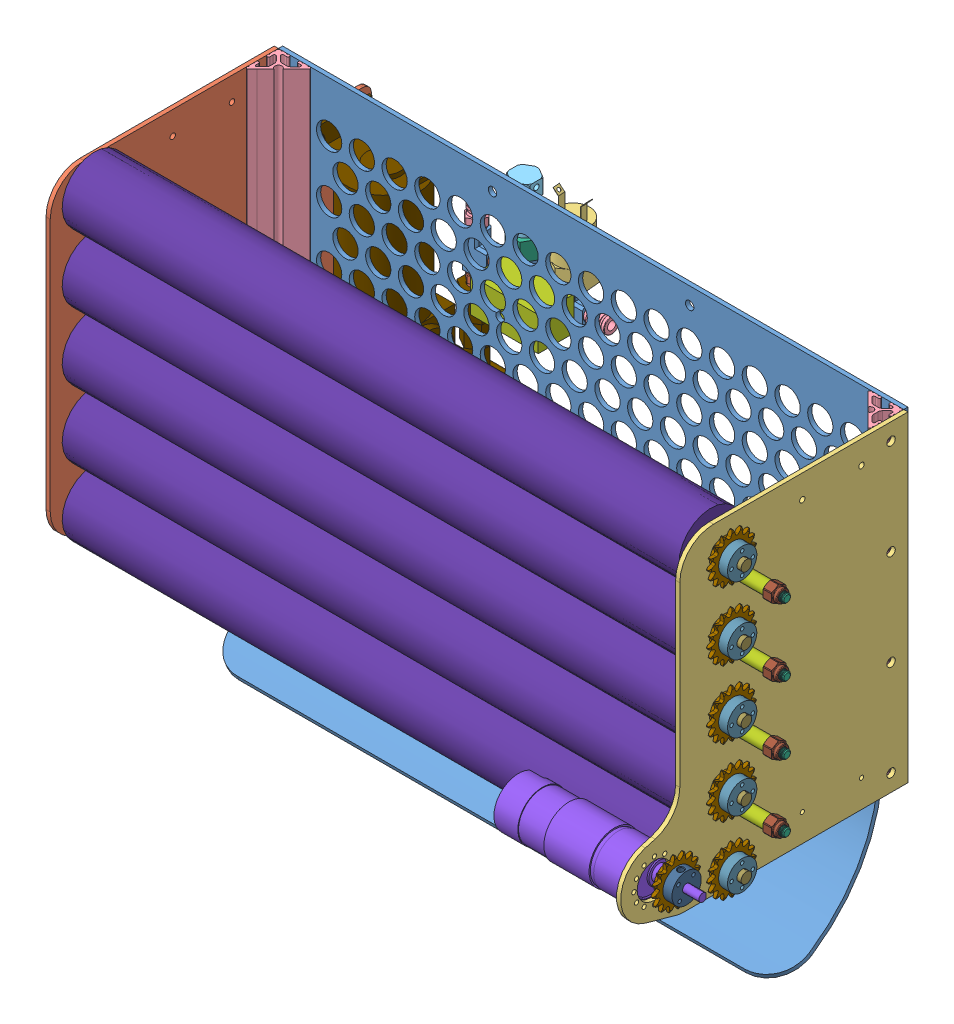
SolidWorks assembly Bubbler 3.1, configuration Default. Lengths in mm.
Overall size (519.86 365.27 285.75).
84 component instances, 25 part files, 49 mates.
Components (placement in the parent):
- Plate Back-1: Plate Back [Model] at origin size (469.9 351.71 78.4)
- Plate Side Right-1: Plate Side Right [Default] at (-238.125 0 88.9) size (3.17 241.3 241.3)
- Plate Side Left-1: Plate Side Left [Default] at (234.95 0 88.9) size (3.17 241.3 215.9)
- Attaching Bracket 8020-1: Attaching Bracket 8020 [Default] at (-222.25 120.65 15.875) x (0 -1 0) z (-1 0 0) size (241.3 25.33 25.33)
- Attaching Bracket 8020-2: Attaching Bracket 8020 [Default] at (222.25 -120.65 15.875) x (0 1 0) z (1 0 0) size (241.3 25.33 25.33)
- 57155K338_SS BALL BEARING-1: 57155K338_SS BALL BEARING [57155K338] at (-236.1724 -101.6 144.78) x (0 -0.021109 0.999777) z (-1 0 0) size (13.89 13.89 4.76)
- 57155K338_SS BALL BEARING-2: 57155K338_SS BALL BEARING [57155K338] at (-236.1724 -50.8 144.78) x (0 -0.021109 0.999777) z (-1 0 0) size (13.89 13.89 4.76)
- 57155K338_SS BALL BEARING-3: 57155K338_SS BALL BEARING [57155K338] at (-236.1724 0 144.78) x (0 -0.021109 0.999777) z (-1 0 0) size (13.89 13.89 4.76)
- 57155K338_SS BALL BEARING-4: 57155K338_SS BALL BEARING [57155K338] at (-236.1724 50.8 144.78) x (0 -0.021109 0.999777) z (-1 0 0) size (13.89 13.89 4.76)
- 57155K338_SS BALL BEARING-5: 57155K338_SS BALL BEARING [57155K338] at (-236.1724 101.6 144.78) x (0 -0.021109 0.999777) z (-1 0 0) size (13.89 13.89 4.76)
- Bolt 1_4-20-1: Bolt 1_4-20 [Tensioner] at (249.2375 -76.2 125.73) x (-1 0 0) z (0 -0.946741 -0.321996) size (41.59 12.83 11.11)
- Bolt 1_4-20-2: Bolt 1_4-20 [Tensioner] at (249.2375 -25.4 125.73) x (-1 0 0) z (0 -0.946741 -0.321996) size (41.59 12.83 11.11)
- Bolt 1_4-20-3: Bolt 1_4-20 [Tensioner] at (249.2375 25.4 125.73) x (-1 0 0) z (0 -0.946741 -0.321996) size (41.59 12.83 11.11)
- Bolt 1_4-20-4: Bolt 1_4-20 [Tensioner] at (249.2375 76.2 125.73) x (-1 0 0) z (0 -0.946741 -0.321996) size (41.59 12.83 11.11)
- Bushing Chain Tensioner-1: Bushing Chain Tensioner [Bubbler] at (238.125 -76.2 125.73) x (0 0 -1) z (1 0 0) size (9.53 9.53 19.05)
- Bushing Chain Tensioner-2: Bushing Chain Tensioner [Bubbler] at (238.125 -25.4 125.73) x (0 0 -1) z (1 0 0) size (9.53 9.53 19.05)
- Bushing Chain Tensioner-3: Bushing Chain Tensioner [Bubbler] at (238.125 25.4 125.73) x (0 0 -1) z (1 0 0) size (9.53 9.53 19.05)
- Bushing Chain Tensioner-4: Bushing Chain Tensioner [Bubbler] at (238.125 76.2 125.73) x (0 0 -1) z (1 0 0) size (9.53 9.53 19.05)
- am-3102NeveRest20-1: am-3102NeveRest20 [Default] at (210.95 -88.9 193.675) x (0 -1 0) z (1 0 0) size (38 38 131.81)
- User Library-Sprocket 25 16T Tetrix-1: User Library-Sprocket 25 16T Tetrix [Default] at (245.65 -88.9 186.675) x (0 0.651596 0.758566) z (-1 0 0) size (36 36 6.8)
- Motor Shaft Hub-1: Motor Shaft Hub [Default] at (251.85 -88.9 186.675) x (0 0.651596 0.758566) z (-1 0 0) size (22 22 9.6)
- Nut Nylock 1-4-20-1: Nut Nylock 1-4-20 [Default] at (257.175 -76.2 125.73) size (9.53 12.45 11.11)
- 5_16 Shaft-1: 5_16 Shaft [Default] at (-249.6661 -101.6 144.78) x (1 0 0) z (0 -0.918452 0.395533) size (508 7.94 7.94)
- 9946K120_SET SCREW SHAFT COLLAR-1: 9946K120_SET SCREW SHAFT COLLAR [9946K12] at (-242.5224 -101.6 144.78) x (0 0 1) z (-1 0 0) size (15.88 15.88 7.94)
- 9946K120_SET SCREW SHAFT COLLAR-2: 9946K120_SET SCREW SHAFT COLLAR [9946K12] at (-242.5224 -50.8 144.78) x (0 0 1) z (-1 0 0) size (15.88 15.88 7.94)
- 9946K120_SET SCREW SHAFT COLLAR-3: 9946K120_SET SCREW SHAFT COLLAR [9946K12] at (-242.5224 0 144.78) x (0 0 1) z (-1 0 0) size (15.88 15.88 7.94)
- 9946K120_SET SCREW SHAFT COLLAR-4: 9946K120_SET SCREW SHAFT COLLAR [9946K12] at (-242.5224 50.8 144.78) x (0 0 1) z (-1 0 0) size (15.88 15.88 7.94)
- 9946K120_SET SCREW SHAFT COLLAR-5: 9946K120_SET SCREW SHAFT COLLAR [9946K12] at (-242.5224 101.6 144.78) x (0 0 1) z (-1 0 0) size (15.88 15.88 7.94)
- 5_16 Shaft-2: 5_16 Shaft [Default] at (-249.6661 -50.8 144.78) x (1 0 0) z (0 -0.918452 0.395533) size (508 7.94 7.94)
- 5_16 Shaft-3: 5_16 Shaft [Default] at (-249.6661 0 144.78) x (1 0 0) z (0 -0.918452 0.395533) size (508 7.94 7.94)
- 5_16 Shaft-4: 5_16 Shaft [Default] at (-249.6661 50.8 144.78) x (1 0 0) z (0 -0.918452 0.395533) size (508 7.94 7.94)
- 5_16 Shaft-5: 5_16 Shaft [Default] at (-249.6661 101.6 144.78) x (1 0 0) z (0 -0.918452 0.395533) size (508 7.94 7.94)
- Axle Shaft Hub 5_16 id-1: Axle Shaft Hub 5_16 id [Default] at (251.8 -101.6 144.78) x (0 0 -1) z (1 0 0) size (22 22 6.7)
- User Library-Sprocket 25 16T Tetrix-2: User Library-Sprocket 25 16T Tetrix [Default] at (245.65 -101.6 144.78) x (0 1 0) z (-1 0 0) size (36 36 6.8)
- 57155K338_SS BALL BEARING-11: 57155K338_SS BALL BEARING [57155K338] at (236.1724 -101.6 144.78) x (0 0.021109 -0.999777) z (1 0 0) size (13.89 13.89 4.76)
- User Library-Sprocket 25 16T Tetrix-3: User Library-Sprocket 25 16T Tetrix [Default] at (245.65 -50.8 144.78) x (0 1 0) z (-1 0 0) size (36 36 6.8)
- User Library-Sprocket 25 16T Tetrix-4: User Library-Sprocket 25 16T Tetrix [Default] at (245.65 0 144.78) x (0 1 0) z (-1 0 0) size (36 36 6.8)
- User Library-Sprocket 25 16T Tetrix-5: User Library-Sprocket 25 16T Tetrix [Default] at (245.65 50.8 144.78) x (0 1 0) z (-1 0 0) size (36 36 6.8)
- User Library-Sprocket 25 16T Tetrix-6: User Library-Sprocket 25 16T Tetrix [Default] at (245.65 101.6 144.78) x (0 1 0) z (-1 0 0) size (36 36 6.8)
- Axle Shaft Hub 5_16 id-2: Axle Shaft Hub 5_16 id [Default] at (251.8 -50.8 144.78) x (0 0 -1) z (1 0 0) size (22 22 6.7)
- Axle Shaft Hub 5_16 id-3: Axle Shaft Hub 5_16 id [Default] at (251.8 0 144.78) x (0 0 -1) z (1 0 0) size (22 22 6.7)
- Axle Shaft Hub 5_16 id-4: Axle Shaft Hub 5_16 id [Default] at (251.8 50.8 144.78) x (0 0 -1) z (1 0 0) size (22 22 6.7)
- Axle Shaft Hub 5_16 id-5: Axle Shaft Hub 5_16 id [Default] at (251.8 101.6 144.78) x (0 0 -1) z (1 0 0) size (22 22 6.7)
- 93960A120_CHROME-PLATED STEEL FLAT WASHER-1: 93960A120_CHROME-PLATED STEEL FLAT WASHER [93960A120] at (-233.7911 -101.6 144.78) size (2.03 18.64 18.64)
- 93960A120_CHROME-PLATED STEEL FLAT WASHER-2: 93960A120_CHROME-PLATED STEEL FLAT WASHER [93960A120] at (233.7911 -101.6 144.78) x (-1 0 0) z (0 0 -1) size (2.03 18.64 18.64)
- 93960A120_CHROME-PLATED STEEL FLAT WASHER-7: 93960A120_CHROME-PLATED STEEL FLAT WASHER [93960A120] at (-233.7911 -50.8 144.78) size (2.03 18.64 18.64)
- 93960A120_CHROME-PLATED STEEL FLAT WASHER-8: 93960A120_CHROME-PLATED STEEL FLAT WASHER [93960A120] at (-233.7911 0 144.78) size (2.03 18.64 18.64)
- 93960A120_CHROME-PLATED STEEL FLAT WASHER-9: 93960A120_CHROME-PLATED STEEL FLAT WASHER [93960A120] at (-233.7911 50.8 144.78) size (2.03 18.64 18.64)
- 93960A120_CHROME-PLATED STEEL FLAT WASHER-10: 93960A120_CHROME-PLATED STEEL FLAT WASHER [93960A120] at (-233.7911 101.6 144.78) size (2.03 18.64 18.64)
- Roller Center-1: Roller Center [Default] at (0 -101.6 144.78) size (463.42 19.05 19.05)
- Roller Center-2: Roller Center [Default] at (0 -50.8 144.78) size (463.42 19.05 19.05)
- Roller Center-3: Roller Center [Default] at (0 0 144.78) size (463.42 19.05 19.05)
- Roller Center-4: Roller Center [Default] at (0 50.8 144.78) size (463.42 19.05 19.05)
- Roller Center-5: Roller Center [Default] at (0 101.6 144.78) size (463.42 19.05 19.05)
- 93960A120_CHROME-PLATED STEEL FLAT WASHER-11: 93960A120_CHROME-PLATED STEEL FLAT WASHER [93960A120] at (233.7911 -50.8 144.78) x (-1 0 0) z (0 0 -1) size (2.03 18.64 18.64)
- 93960A120_CHROME-PLATED STEEL FLAT WASHER-12: 93960A120_CHROME-PLATED STEEL FLAT WASHER [93960A120] at (233.7911 0 144.78) x (-1 0 0) z (0 0 -1) size (2.03 18.64 18.64)
- 93960A120_CHROME-PLATED STEEL FLAT WASHER-13: 93960A120_CHROME-PLATED STEEL FLAT WASHER [93960A120] at (233.7911 50.8 144.78) x (-1 0 0) z (0 0 -1) size (2.03 18.64 18.64)
- 93960A120_CHROME-PLATED STEEL FLAT WASHER-14: 93960A120_CHROME-PLATED STEEL FLAT WASHER [93960A120] at (233.7911 101.6 144.78) x (-1 0 0) z (0 0 -1) size (2.03 18.64 18.64)
- 57155K338_SS BALL BEARING-16: 57155K338_SS BALL BEARING [57155K338] at (236.1724 -50.8 144.78) x (0 0.021109 -0.999777) z (1 0 0) size (13.89 13.89 4.76)
- 57155K338_SS BALL BEARING-17: 57155K338_SS BALL BEARING [57155K338] at (236.1724 0 144.78) x (0 0.021109 -0.999777) z (1 0 0) size (13.89 13.89 4.76)
- 57155K338_SS BALL BEARING-18: 57155K338_SS BALL BEARING [57155K338] at (236.1724 50.8 144.78) x (0 0.021109 -0.999777) z (1 0 0) size (13.89 13.89 4.76)
- 57155K338_SS BALL BEARING-19: 57155K338_SS BALL BEARING [57155K338] at (236.1724 101.6 144.78) x (0 0.021109 -0.999777) z (1 0 0) size (13.89 13.89 4.76)
- Roller-1: Roller [Default] at (0 -101.6 144.78) x (1 0 0) z (0 -0.883671 0.468109) size (463.42 48.26 48.26)
- Roller-2: Roller [Default] at (0 -50.8 144.78) x (1 0 0) z (0 -0.883671 0.468109) size (463.42 48.26 48.26)
- Roller-3: Roller [Default] at (0 0 144.78) x (1 0 0) z (0 -0.883671 0.468109) size (463.42 48.26 48.26)
- Roller-4: Roller [Default] at (0 50.8 144.78) x (1 0 0) z (0 -0.883671 0.468109) size (463.42 48.26 48.26)
- Roller-5: Roller [Default] at (0 101.6 144.78) x (1 0 0) z (0 -0.883671 0.468109) size (463.42 48.26 48.26)
- Nut Nylock 1-4-20-2: Nut Nylock 1-4-20 [Default] at (257.175 -25.4 125.73) size (9.53 12.45 11.11)
- Nut Nylock 1-4-20-3: Nut Nylock 1-4-20 [Default] at (257.175 25.4 125.73) size (9.53 12.45 11.11)
- Nut Nylock 1-4-20-4: Nut Nylock 1-4-20 [Default] at (257.175 76.2 125.73) size (9.53 12.45 11.11)
- Compressor_90C-1: Compressor_90C [Default] at (-192.278 -15.875 -33.3375) x (0 0 -1) z (0 -1 0) size (53.59 121.98 156.21)
- High Pressure Block-1: High Pressure Block [Default] at (-50.292 29.083 -33.3375) size (111.06 101.73 31.53)
  - UnionTee-1: UnionTee [Default] x (1 0 0) z (0 -1 0) size (26.92 12.5 19.71)
  - HexNipple_0.125-2: HexNipple_0.125 [Default] at (-18.034 0 0) x (0 0.057278 0.998358) z (-1 0 0) size (12.83 11.11 24.64)
  - PressureSwitch-1: PressureSwitch [Default] at (0 5.334 0) x (0.995826 0 -0.09127) z (0.09127 0 0.995826) size (25.4 66.04 29.33)
  - PrestolokMaleConnector-1: PrestolokMaleConnector [Default] at (-72.136 6.858 0) x (0 1 0) z (0.667866 0 -0.744282) size (22.45 14.42 12.7)
  - ReliefValve-1: ReliefValve [Default] at (-36.068 65.568 0) size (17.5 44 20.05)
  - Adapter_0.25_0.125-1: Adapter_0.25_0.125 [Default] at (-36.068 28.956 0) x (0.999751 0 -0.022334) z (0.022334 0 0.999751) size (22 26.92 19.05)
  - UnionTee-3: UnionTee [Default] at (-36.068 0 0) x (1 0 0) z (0 -1 0) size (26.92 12.5 19.71)
  - UnionTee-4: UnionTee [Default] at (-72.136 0 0) x (0 -1 0) z (-1 0 0) size (26.92 12.5 19.71)
  - HexNipple_0.125-3: HexNipple_0.125 [Default] at (-54.102 0 0) x (0 0.536676 0.843789) z (-1 0 0) size (12.83 11.11 24.64)
  - PrestolokMaleConnector-2: PrestolokMaleConnector [Default] at (6.858 0 0) x (1 0 0) z (0 0.971535 0.236895) size (22.45 14.42 12.7)
  - HexNipple_0.125-4: HexNipple_0.125 [Default] at (-72.136 -18.034 0) x (0.928821 0 -0.37053) z (0 1 0) size (12.83 11.11 24.64)
- Pneumatics Spacers-1: Pneumatics Spacers [Default] at (-68.326 29.083 0) x (-1 0 0) z (0 0 1) size (50.8 25.4 26.99)
Mates (geometry in assembly coordinates):
- Coincident1: coincident anti-aligned: plane of Plate Back-1 through (0 0 3.175) normal (0 0 1); plane of Attaching Bracket 8020-1 through (-231.8004 -120.65 3.175) normal (0 0 -1)
- Coincident2: coincident anti-aligned: plane of Plate Side Right-1 through (-234.95 0 88.9) normal (1 0 0); plane of Attaching Bracket 8020-1 through (-234.95 -120.65 9.5419) normal (-1 0 0)
- Coincident3: coincident aligned: plane of Plate Back-1 through (234.95 -120.65 3.175) normal (0 -1 0); plane of Attaching Bracket 8020-1 through (-216.4249 -120.65 3.175) normal (0 -1 0)
- Coincident4: coincident aligned: plane of Plate Side Right-1 through (-234.95 -120.65 174.625) normal (0 -1 0); plane of Attaching Bracket 8020-1 through (-216.4249 -120.65 3.175) normal (0 -1 0)
- Coincident5: coincident anti-aligned: plane of Plate Back-1 through (0 0 3.175) normal (0 0 1); plane of Plate Side Right-1 through (-234.95 120.65 3.175) normal (0 0 -1)
- Coincident7: coincident anti-aligned: plane of Plate Side Left-1 through (234.95 -88.9 193.675) normal (-1 0 0); plane of Attaching Bracket 8020-2 through (234.95 120.65 9.5419) normal (1 0 0)
- Coincident8: coincident anti-aligned: plane of Plate Back-1 through (0 0 3.175) normal (0 0 1); plane of Plate Side Left-1 through (238.125 120.65 3.175) normal (0 0 -1)
- Coincident9: coincident aligned: plane of Plate Side Left-1 through (238.125 -120.65 174.625) normal (0 -1 0); plane of Attaching Bracket 8020-2 through (216.4249 -120.65 3.175) normal (0 -1 0)
- Concentric1: concentric aligned: cylinder of Plate Side Right-1 through (-234.95 -101.6 144.78) axis (-1 0 0) radius 6.35; cylinder of 57155K338_SS BALL BEARING-1 through (-238.1567 -101.6 144.78) axis (-1 0 0) radius 6.35
- Coincident10: coincident anti-aligned: plane of Plate Side Right-1 through (-234.95 0 88.9) normal (1 0 0); plane of 57155K338_SS BALL BEARING-1 through (-234.95 -96.0581 144.897) normal (-1 0 0)
- Concentric2: concentric aligned: cylinder of Plate Side Left-1 through (234.95 -76.2 125.73) axis (1 0 0) radius 3.175; cylinder of Bolt 1_4-20-1 through (269.875 -76.2 125.73) axis (1 0 0) radius 3.175
- Coincident11: coincident anti-aligned: plane of Plate Side Left-1 through (234.95 -88.9 193.675) normal (-1 0 0); plane of Bolt 1_4-20-1 through (234.95 -75.1777 122.7241) normal (1 0 0)
- Concentric3: concentric anti-aligned: cylinder of Bolt 1_4-20-1 through (269.875 -76.2 125.73) axis (1 0 0) radius 3.175; cylinder of Bushing Chain Tensioner-1 through (257.175 -76.2 125.73) axis (-1 0 0) radius 3.175
- Coincident12: coincident anti-aligned: plane of Plate Side Left-1 through (238.125 -88.9 193.675) normal (1 0 0); plane of Bushing Chain Tensioner-1 through (238.125 -76.2 125.73) normal (-1 0 0)
- Concentric4: concentric aligned: cylinder of Plate Side Left-1 through (238.125 -88.9 193.675) axis (-1 0 0) radius 25.4; cylinder of am-3102NeveRest20-1 through (234.95 -88.9 193.675) axis (-1 0 0) radius 18.5
- Coincident13: coincident anti-aligned: plane of Plate Side Left-1 through (234.95 -88.9 193.675) normal (-1 0 0); plane of am-3102NeveRest20-1 through (234.95 -88.9 193.675) normal (1 0 0)
- Concentric5: concentric anti-aligned: cylinder of User Library-Sprocket 25 16T Tetrix-1 through (248.45 -88.9 186.675) axis (-1 0 0) radius 4; cylinder of Motor Shaft Hub-1 through (245.65 -88.9 186.675) axis (1 0 0) radius 4
- Concentric6: concentric aligned: cylinder of User Library-Sprocket 25 16T Tetrix-1 through (248.45 -83.6872 192.7435) axis (-1 0 0) radius 1.8; cylinder of Motor Shaft Hub-1 through (248.45 -83.6872 192.7435) axis (-1 0 0) radius 1.3526
- Coincident14: coincident anti-aligned: plane of User Library-Sprocket 25 16T Tetrix-1 through (248.45 -76.5543 176.0703) normal (1 0 0); plane of Motor Shaft Hub-1 through (248.45 -88.9 186.675) normal (-1 0 0)
- Concentric7: concentric aligned: cylinder of am-3102NeveRest20-1 through (257.25 -88.9 186.675) axis (-1 0 0) radius 3; cylinder of User Library-Sprocket 25 16T Tetrix-1 through (248.45 -88.9 186.675) axis (-1 0 0) radius 4
- Coincident15: coincident anti-aligned: plane of am-3102NeveRest20-1 through (241.65 -88.9 186.675) normal (1 0 0); plane of User Library-Sprocket 25 16T Tetrix-1 through (241.65 -88.9 186.675) normal (-1 0 0)
- Concentric8: concentric anti-aligned: cylinder of Bolt 1_4-20-1 through (269.875 -76.2 125.73) axis (1 0 0) radius 3.175; cylinder of Nut Nylock 1-4-20-1 through (257.175 -76.2 125.73) axis (-1 0 0) radius 3.175
- Coincident16: coincident anti-aligned: plane of Bushing Chain Tensioner-1 through (257.175 -76.2 125.73) normal (1 0 0); plane of Nut Nylock 1-4-20-1 through (257.175 -76.2 125.73) normal (-1 0 0)
- Concentric9: concentric aligned: cylinder of 57155K338_SS BALL BEARING-1 through (-238.1567 -101.6 144.78) axis (-1 0 0) radius 3.9688; cylinder of 5_16 Shaft-1 through (258.3339 -101.6 144.78) axis (-1 0 0) radius 3.9688
- Concentric10: concentric anti-aligned: cylinder of 5_16 Shaft-1 through (258.3339 -101.6 144.78) axis (-1 0 0) radius 3.9688; cylinder of 9946K120_SET SCREW SHAFT COLLAR-1 through (-246.4911 -101.6 144.78) axis (1 0 0) radius 3.9688
- Coincident17: coincident anti-aligned: plane of 57155K338_SS BALL BEARING-1 through (-238.5536 -97.4337 144.868) normal (-1 0 0); plane of 9946K120_SET SCREW SHAFT COLLAR-1 through (-238.5536 -101.6 144.78) normal (1 0 0)
- Distance1: distance = 3.175 mm aligned: plane of 5_16 Shaft-1 through (-249.6661 -101.6 144.78) normal (-1 0 0); plane of 9946K120_SET SCREW SHAFT COLLAR-1 through (-246.4911 -101.6 144.78) normal (-1 0 0)
- Concentric11: concentric anti-aligned: cylinder of 5_16 Shaft-1 through (258.3339 -101.6 144.78) axis (-1 0 0) radius 3.9688; cylinder of Axle Shaft Hub 5_16 id-1 through (248.45 -101.6 144.78) axis (1 0 0) radius 3.9688
- Concentric12: concentric anti-aligned: cylinder of Axle Shaft Hub 5_16 id-1 through (248.45 -101.6 144.78) axis (1 0 0) radius 3.9688; cylinder of User Library-Sprocket 25 16T Tetrix-2 through (248.45 -101.6 144.78) axis (-1 0 0) radius 4
- Concentric13: concentric anti-aligned: cylinder of Axle Shaft Hub 5_16 id-1 through (255.15 -101.6 152.78) axis (1 0 0) radius 1.3526; cylinder of User Library-Sprocket 25 16T Tetrix-2 through (248.45 -101.6 152.78) axis (-1 0 0) radius 1.8
- Coincident19: coincident anti-aligned: plane of Axle Shaft Hub 5_16 id-1 through (248.45 -101.6 144.78) normal (-1 0 0); plane of User Library-Sprocket 25 16T Tetrix-2 through (248.45 -101.6 128.505) normal (1 0 0)
- Coincident20: coincident aligned: plane of User Library-Sprocket 25 16T Tetrix-1 through (248.45 -76.5543 176.0703) normal (1 0 0); plane of User Library-Sprocket 25 16T Tetrix-2 through (248.45 -101.6 128.505) normal (1 0 0)
- Concentric14: concentric aligned: cylinder of 5_16 Shaft-1 through (258.3339 -101.6 144.78) axis (-1 0 0) radius 3.9688; cylinder of 93960A120_CHROME-PLATED STEEL FLAT WASHER-1 through (-231.7591 -101.6 144.78) axis (-1 0 0) radius 3.9624
- Coincident21: coincident anti-aligned: plane of 57155K338_SS BALL BEARING-1 through (-233.7911 -97.0239 144.8766) normal (1 0 0); plane of 93960A120_CHROME-PLATED STEEL FLAT WASHER-1 through (-233.7911 -101.6 144.78) normal (-1 0 0)
- Coincident22: coincident aligned: plane of Roller Center-1 through (0 -101.6 144.78) normal (1 0 0); plane of assembly through (0 0 0) normal (1 0 0)
- Concentric15: concentric aligned: cylinder of 5_16 Shaft-1 through (258.3339 -101.6 144.78) axis (-1 0 0) radius 3.9688; cylinder of Roller Center-1 through (231.7115 -101.6 144.78) axis (-1 0 0) radius 3.9688
- Coincident23: coincident aligned: plane of Roller-1; plane of assembly through (0 0 0) normal (1 0 0)
- Concentric16: concentric aligned: cylinder of Roller Center-1 through (231.7115 -101.6 144.78) axis (-1 0 0) radius 9.525; cylinder of Roller-1 through (231.7115 -101.6 144.78) axis (-1 0 0) radius 9.525
- Parallel1: parallel anti-aligned: plane of am-3102NeveRest20-1; plane of assembly through (0 0 0) normal (0 1 0)
- Coincident24: coincident anti-aligned: plane of Plate Back-1 through (-234.95 -120.65 3.175) normal (-1 0 0); plane of Plate Side Right-1 through (-234.95 0 88.9) normal (1 0 0)
- Coincident137: coincident anti-aligned: plane of Plate Side Right-1 through (-234.95 0 88.9) normal (1 0 0); plane of Compressor_90C-1 through (-234.95 54.61 -33.3375) normal (-1 0 0)
- Width8: width aligned: plane of Compressor_90C-1 through (-192.278 -93.98 -33.3375) normal (0 -1 0); plane of Compressor_90C-1 through (-192.278 62.23 -33.3375) normal (0 1 0); plane of Plate Side Right-1 through (-234.95 63.5 3.175) normal (0 1 0); plane of Plate Side Right-1 through (-234.95 -95.25 3.175) normal (0 -1 0)
- Width9: width aligned: plane of Compressor_90C-1 through (-192.278 -76.708 -6.6675) normal (0 0 1); plane of Compressor_90C-1 through (-192.278 -76.708 -60.0075) normal (0 0 -1); plane of Plate Side Right-1 through (-234.95 57.15 -66.675) normal (0 0 -1); plane of Plate Back-1 through (0 0 0) normal (0 0 -1)
- Concentric17: concentric aligned: cylinder of Compressor_90C-1 through (-122.428 6.477 -33.3375) axis (0 -1 0) radius 5.715; cylinder of High Pressure Block-1/HexNipple_0.125-4 through (-122.428 23.368 -33.3375) axis (0 -1 0) radius 5.1435
- Parallel2: parallel anti-aligned: plane of Plate Back-1 through (0 0 0) normal (0 0 -1); plane of High Pressure Block-1/UnionTee-4 through (-126.9386 29.083 -27.0891) normal (0 0 1)
- Distance2: distance = 2.032 mm anti-aligned: plane of High Pressure Block-1/HexNipple_0.125-4 through (-122.428 8.509 -33.3375) normal (0 -1 0); plane of Compressor_90C-1 through (-192.278 6.477 -33.3375) normal (0 1 0)
- Coincident139: coincident anti-aligned: plane of Plate Back-1 through (0 0 0) normal (0 0 -1); plane of Pneumatics Spacers-1 through (-68.326 29.083 0) normal (0 0 1)
- Width10: width aligned: plane of Pneumatics Spacers-1 through (-93.726 16.383 -26.9875) normal (0 -1 0); plane of Pneumatics Spacers-1 through (-93.726 41.783 -26.9875) normal (0 1 0); plane of High Pressure Block-1/UnionTee-3 through (-86.36 22.8346 -37.8481) normal (0 -1 0); plane of High Pressure Block-1/UnionTee-3 through (-86.36 35.3314 -28.8269) normal (0 1 0)
- Width11: width anti-aligned: plane of Pneumatics Spacers-1 through (-42.926 41.783 -26.9875) normal (1 0 0); plane of Pneumatics Spacers-1 through (-93.726 41.783 -26.9875) normal (-1 0 0); plane of High Pressure Block-1/UnionTee-3 through (-72.898 29.083 -33.3375) normal (1 0 0); plane of High Pressure Block-1/UnionTee-1 through (-63.754 29.083 -33.3375) normal (-1 0 0)
